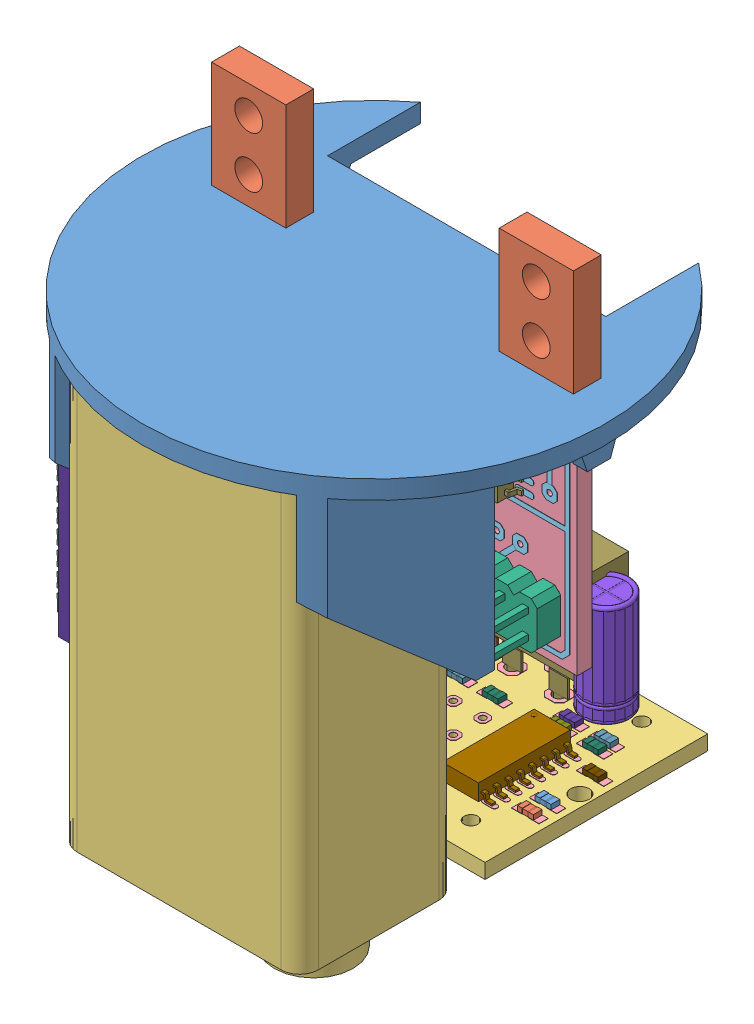
SolidWorks assembly Elektro, configuration Standard. Lengths in mm.
Overall size (51.6 63.5 45.81).
65 component instances, 61 part files, 17 mates.
Components (placement in the parent):
- E-Part-1: E-Part [Standard] at (0.3501 -2.1253 50) size (50 27 45)
- E-Befestigung-1: E-Befestigung [Standard] at (-10.1499 -0.1253 49) size (8 11.5 3)
- E-Befestigung-2: E-Befestigung [Standard] at (20.8501 -0.1253 49) size (8 11.5 3)
- 9V-1: 9V [Standard] at (-12.6499 -2.1253 54) x (0 0 -1) z (-1 0 0) size (17 50 26)
- Zeitschaltung-1: Zeitschaltung [Standard] at (0.3501 -17.1253 42.3) x (0 1 0) z (0 0 1) size (30 30 20.34)
  - Zeitschaltung_Board-1: Zeitschaltung_Board [Standard] at origin size (30 30 1.6)
  - Zeitschaltung_PadsAndTracks-1: Zeitschaltung_PadsAndTracks [Standard] at origin size (28.67 28.55 1.67)
  - Zeitschaltung_K1-1: Zeitschaltung_K1 [Standard] at origin size (2.54 5.08 10.74) (hidden)
  - Zeitschaltung_K2-1: Zeitschaltung_K2 [Standard] at origin size (7.62 2.54 10.74) (hidden)
  - Zeitschaltung_K3-1: Zeitschaltung_K3 [Standard] at origin size (7.62 2.54 10.74) (hidden)
  - Zeitschaltung_K4-1: Zeitschaltung_K4 [Standard] at origin size (5.08 7.62 10.74)
  - Zeitschaltung_K6-1: Zeitschaltung_K6 [Standard] at origin size (2.54 5.08 10.74) (hidden)
  - Zeitschaltung_IC3-1: Zeitschaltung_IC3 [Standard] at origin size (8.8 8.8 1.61)
  - Zeitschaltung_D5-1: Zeitschaltung_D5 [Standard] at origin size (3.7 3 2.09)
  - Zeitschaltung_R1-1: Zeitschaltung_R1 [Standard] at origin size (3.2 1.6 0.61)
  - Zeitschaltung_R5-1: Zeitschaltung_R5 [Standard] at origin size (3.2 1.6 0.61)
  - Zeitschaltung_K5-1: Zeitschaltung_K5 [Standard] at origin size (17.78 2.54 12) (hidden)
  - Zeitschaltung_R4-1: Zeitschaltung_R4 [Standard] at origin size (3.2 1.6 0.61)
  - Zeitschaltung_X2-1: Zeitschaltung_X2 [Standard] at origin size (5 6.04 1.86)
  - Zeitschaltung_C2-1: Zeitschaltung_C2 [Standard] at origin size (3.2 1.6 0.61)
  - Zeitschaltung_R2-1: Zeitschaltung_R2 [Standard] at origin size (4.7 6.5 7)
  - Zeitschaltung_T1-1: Zeitschaltung_T1 [Standard] at origin size (10.42 6.5 2.38)
  - Zeitschaltung_K7-1: Zeitschaltung_K7 [Standard] at origin size (2.54 5.08 12) (hidden)
  - Zeitschaltung_T2-1: Zeitschaltung_T2 [Standard] at origin size (3 2.6 1.1)
- Funkchip-1: Funkchip [Standard] at (-15.4499 -13.7253 44) x (0 -1 0) z (-1 0 0) size (18.4 23.4 12)
  - Funkchip_Board-1: Funkchip_Board [Standard] at origin size (18.4 23.4 1.6)
  - Funkchip_PadsAndTracks-1: Funkchip_PadsAndTracks [Standard] at origin size (17.1 22.3 1.67)
  - Funkchip_IC1-1: Funkchip_IC1 [Standard] at origin size (16.1 15.9 4.2)
  - Funkchip_R1-1: Funkchip_R1 [Standard] at origin size (8.15 1.8 3.85)
  - Funkchip_K1-1: Funkchip_K1 [Standard] at origin size (17.78 2.54 12) (hidden)
- Bewegungsmelder-1: Bewegungsmelder [Standard] at (-15.6755 -44.4022 54) x (1 0 0) z (0 1 0) size (32 24.8 16.02)
  - Bewegungsmelder_Board-1: Bewegungsmelder_Board [Standard] at origin size (32 24 1.6)
  - Bewegungsmelder_PadsAndTracks-1: Bewegungsmelder_PadsAndTracks [Standard] at origin size (30.89 22.22 1.67)
  - Bewegungsmelder_K1-1: Bewegungsmelder_K1 [Standard] at origin size (7.62 2.54 12) (hidden)
  - Bewegungsmelder_GEH1-1: Bewegungsmelder_GEH1 [Standard] at origin size (5 5 13.11)
  - Bewegungsmelder_GEH2-1: Bewegungsmelder_GEH2 [Standard] at origin size (5 5 13.11)
  - Bewegungsmelder_GEH3-1: Bewegungsmelder_GEH3 [Standard] at origin size (5 5 13.11)
  - Bewegungsmelder_GEH4-1: Bewegungsmelder_GEH4 [Standard] at origin size (5 5 13.11)
  - Bewegungsmelder_GEH5-1: Bewegungsmelder_GEH5 [Standard] at origin size (6.2 9.9 1.76)
  - Bewegungsmelder_T2-1: Bewegungsmelder_T2 [Standard] at origin size (5 4.05 1.65)
  - Bewegungsmelder_R1-1: Bewegungsmelder_R1 [Standard] at origin size (9.8 5.2 16.02)
  - Bewegungsmelder_R2-1: Bewegungsmelder_R2 [Standard] at origin size (9.8 5.2 16.02)
  - Bewegungsmelder_D1-1: Bewegungsmelder_D1 [Standard] at origin size (3.5 1.5 1.5)
  - Bewegungsmelder_GEH6-1: Bewegungsmelder_GEH6 [Standard] at origin size (1.7 0.95 0.55)
  - Bewegungsmelder_GEH7-1: Bewegungsmelder_GEH7 [Standard] at origin size (1.7 0.95 0.55)
  - Bewegungsmelder_GEH8-1: Bewegungsmelder_GEH8 [Standard] at origin size (1.7 0.95 0.55)
  - Bewegungsmelder_GEH9-1: Bewegungsmelder_GEH9 [Standard] at origin size (1.7 0.95 0.55)
  - Bewegungsmelder_GEH10-1: Bewegungsmelder_GEH10 [Standard] at origin size (1.7 0.95 0.55)
  - Bewegungsmelder_GEH11-1: Bewegungsmelder_GEH11 [Standard] at origin size (1.7 0.95 0.55)
  - Bewegungsmelder_GEH12-1: Bewegungsmelder_GEH12 [Standard] at origin size (1.7 0.95 0.55)
  - Bewegungsmelder_GEH13-1: Bewegungsmelder_GEH13 [Standard] at origin size (1.7 0.95 0.55)
  - Bewegungsmelder_GEH14-1: Bewegungsmelder_GEH14 [Standard] at origin size (1.7 0.95 0.55)
  - Bewegungsmelder_GEH15-1: Bewegungsmelder_GEH15 [Standard] at origin size (1.7 0.95 0.55)
  - Bewegungsmelder_GEH16-1: Bewegungsmelder_GEH16 [Standard] at origin size (1.7 0.95 0.55)
  - Bewegungsmelder_GEH17-1: Bewegungsmelder_GEH17 [Standard] at origin size (1.7 0.95 0.55)
  - Bewegungsmelder_GEH18-1: Bewegungsmelder_GEH18 [Standard] at origin size (1.7 0.95 0.55)
  - Bewegungsmelder_GEH19-1: Bewegungsmelder_GEH19 [Standard] at origin size (1.7 0.95 0.55)
  - Bewegungsmelder_GEH20-1: Bewegungsmelder_GEH20 [Standard] at origin size (1.7 0.95 0.55)
  - Bewegungsmelder_GEH21-1: Bewegungsmelder_GEH21 [Standard] at origin size (1.7 0.95 0.55)
  - Bewegungsmelder_GEH22-1: Bewegungsmelder_GEH22 [Standard] at origin size (1.7 0.95 0.55)
  - Bewegungsmelder_GEH23-1: Bewegungsmelder_GEH23 [Standard] at origin size (1.7 0.95 0.55)
  - Bewegungsmelder_GEH24-1: Bewegungsmelder_GEH24 [Standard] at origin size (1.7 0.95 0.55)
  - Bewegungsmelder_GEH25-1: Bewegungsmelder_GEH25 [Standard] at origin size (1.7 0.95 0.55)
  - Bewegungsmelder_GEH26-1: Bewegungsmelder_GEH26 [Standard] at origin size (1.7 0.95 0.55)
  - Bewegungsmelder_GEH27-1: Bewegungsmelder_GEH27 [Standard] at origin size (0.95 1.7 0.55)
Mates (geometry in assembly coordinates):
- Deckungsgleich5: coincident anti-aligned: plane of E-Part-1 through (0.3501 -0.1253 50) normal (0 1 0); plane of E-Befestigung-1 through (-10.1499 -0.1253 49) normal (0 -1 0)
- Deckungsgleich6: coincident anti-aligned: plane of E-Part-1 through (0.3501 -0.1253 50) normal (0 1 0); plane of E-Befestigung-2 through (20.8501 -0.1253 49) normal (0 -1 0)
- Abstand2: distance = 10.5 mm: line of E-Befestigung-1 through (-10.1499 -0.1253 49) axis (0 0 -1); line of E-Part-1 through (0.3501 -0.1253 22.8782) axis (0 0 1)
- Abstand3: distance = 12.5 mm: line of E-Befestigung-2 through (12.8501 -0.1253 46) axis (0 0 1); line of E-Part-1 through (0.3501 -0.1253 22.8782) axis (0 0 1)
- Abstand6: distance = 4 mm: line of E-Befestigung-2 through (20.8501 -0.1253 46) axis (-1 0 0); line of E-Part-1 through (36.8365 -0.1253 50) axis (-1 0 0)
- Abstand7: distance = 4 mm: line of E-Befestigung-1 through (-10.1499 -0.1253 46) axis (-1 0 0); line of E-Part-1 through (36.8365 -0.1253 50) axis (-1 0 0)
- Deckungsgleich14: coincident anti-aligned: plane of E-Part-1 through (0.3501 -2.1253 50) normal (0 -1 0); plane of 9V-1 through (-12.6499 -2.1253 54) normal (0 1 0)
- Deckungsgleich15: coincident anti-aligned: plane of E-Part-1 through (0.3501 -2.1253 50) normal (0 -1 0); plane of Zeitschaltung-1/Zeitschaltung_Board-1 through (15.3501 -2.1253 41.5) normal (0 1 0)
- Deckungsgleich27: coincident anti-aligned: plane of E-Part-1 through (0.3501 -13.7253 50) normal (0 -1 0); plane of Funkchip-1/Funkchip_Board-1 through (-14.6499 -13.7253 67.4) normal (0 1 0)
- Deckungsgleich20: coincident anti-aligned: plane of E-Part-1 through (-12.6499 -27.1253 54) normal (1 0 0); plane of 9V-1 through (-12.6499 -52.1253 54) normal (-1 0 0)
- Deckungsgleich21: coincident anti-aligned: plane of E-Part-1 through (13.3501 -27.1253 54) normal (0 0 1); plane of 9V-1 through (-12.6499 -52.1253 54) normal (0 0 -1)
- Deckungsgleich23: coincident anti-aligned: plane of E-Part-1 through (15.3501 -3.1253 41.5) normal (0 0 1); plane of Zeitschaltung-1/Zeitschaltung_Board-1 through (-14.6499 -32.1253 41.5) normal (0 0 -1)
- Deckungsgleich24: coincident anti-aligned: plane of E-Part-1 through (15.3501 22.8747 17.4147) normal (-1 0 0); plane of Zeitschaltung-1/Zeitschaltung_Board-1 through (15.3501 -32.1253 41.5) normal (1 0 0)
- Deckungsgleich26: coincident anti-aligned: plane of E-Part-1 through (-14.6499 -13.7253 44) normal (0 0 1); plane of Funkchip-1/Funkchip_Board-1 through (-14.6499 -13.7253 44) normal (0 0 -1)
- Deckungsgleich28: coincident anti-aligned: plane of E-Part-1 through (-16.2499 -13.7253 44) normal (1 0 0); plane of Funkchip-1/Funkchip_Board-1 through (-16.2499 -13.7253 67.4) normal (-1 0 0)
- Parallel1: parallel aligned: plane of E-Part-1 through (0.3501 -2.1253 50) normal (0 -1 0); plane of Bewegungsmelder-1/Bewegungsmelder_Board-1 through (-15.6755 -45.2022 30) normal (0 -1 0)
- Deckungsgleich30: coincident anti-aligned: plane of 9V-1 through (-12.6499 -52.1253 54) normal (0 0 -1); plane of Bewegungsmelder-1/Bewegungsmelder_Board-1 through (-15.6755 -45.2022 54) normal (0 0 1)
